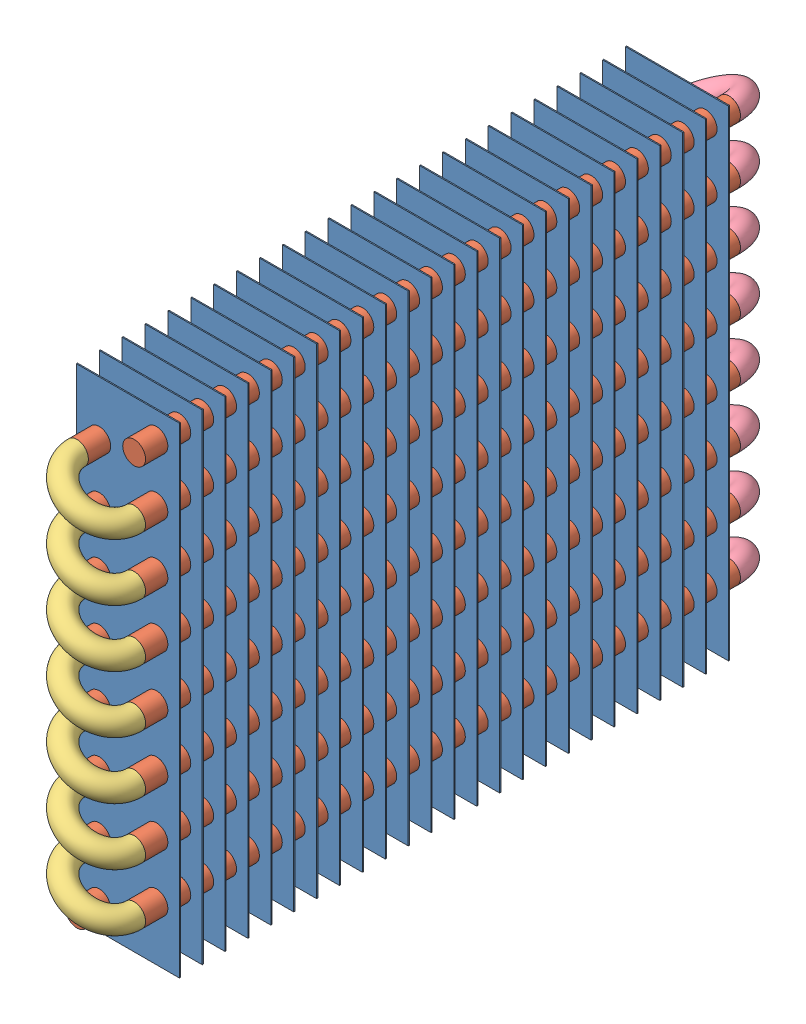
SolidWorks assembly Montage_Radiador, configuration Default. Lengths in mm.
Overall size (45 210 297.95).
5 component instances, 4 part files, 12 mates.
Components (placement in the parent):
- Placa-1: Placa [Valor predeterminado] at origin size (45 210 240.5)
- Tubo-1: Tubo [Valor predeterminado] at (12.5 -81.25 120) size (10 185 260)
- Tubo-2: Tubo [Valor predeterminado] at (-12.5 -93.75 120) size (10 185 260)
- Cotovelo-1: Cotovelo [Valor predeterminado] at (0 75 250) x (-1 0 0) z (0 0 1) size (35 172.5 18.98)
- Cotovelo_2-1: Cotovelo_2 [Valor predeterminado] at (0 -87.5 -10) x (-1 0 0) z (0 0 -1) size (35 197.5 18.98)
Mates (geometry in assembly coordinates):
- Concêntrico1: concentric aligned: circle of Placa-1; circle of Tubo-1
- Distância2: distance = 9.75 mm aligned: plane of Tubo-1 through (12.5 -81.25 250) normal (0 0 1); plane of Placa-1 through (0 0 240.25) normal (0 0 1)
- Concêntrico2: concentric aligned: circle of Placa-1; circle of Tubo-1
- Concêntrico3: concentric aligned: circle of Placa-1; circle of Tubo-2
- Concêntrico4: concentric aligned: circle of Placa-1; circle of Tubo-2
- Distância3: distance = 9.75 mm aligned: plane of Tubo-2 through (-12.5 81.25 250) normal (0 0 1); plane of Placa-1 through (0 0 240.25) normal (0 0 1)
- Concêntrico5: concentric: circle of Tubo-2; circle of Cotovelo-1
- Concêntrico10: concentric: circle of Tubo-1; circle of Cotovelo-1
- Concêntrico16: concentric: circle of Tubo-1; circle of Cotovelo_2-1
- Concêntrico17: concentric: circle of Tubo-2; circle of Cotovelo_2-1
- Coincidente22: coincident anti-aligned: plane of Tubo-2 through (-12.5 81.25 250) normal (0 0 1); plane of Cotovelo-1 through (-12.5 81.25 250) normal (0 0 -1)
- Coincidente23: coincident aligned: circle of Tubo-1; plane of Cotovelo_2-1 through (12.5 93.75 -10) normal (0 0 1)
